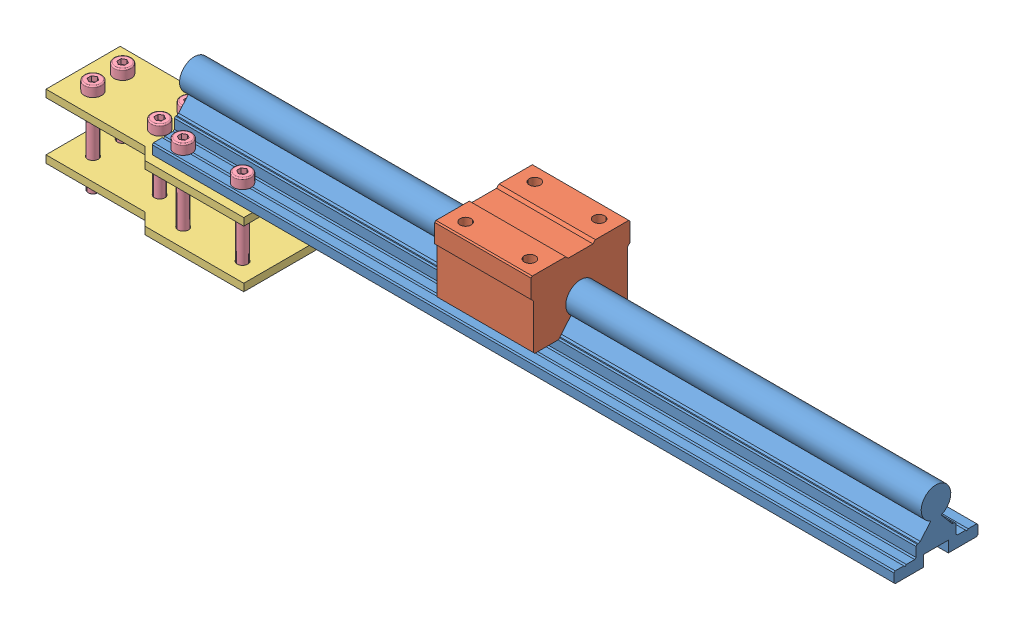
SolidWorks assembly SBR12, configuration 默认. Lengths in mm.
Overall size (345 72.4 40).
20 component instances, 5 part files, 34 mates.
Components (placement in the parent):
- SBR12SA-1: SBR12SA [默认] at (-161.757 5.2695 300) size (300 26.4 34)
- SBR12UU-1: SBR12UU [默认] at (-5.5215 16.7426 300) x (0 0 1) z (-1 0 0) size (40 27.6 39)
- 滑轨固定玻纤下-1: 滑轨固定玻纤下 [Default] at (-161.757 -6.8574 300) x (-1 0 0) z (0 -1 0) size (85 40 3)
- 滑轨固定玻纤下-2: 滑轨固定玻纤下 [Default] at (-161.757 -29.8574 300) x (-1 0 0) z (0 -1 0) size (85 40 3)
- hexagon socket head cap screws gb-3: hexagon socket head cap screws gb [GB_FASTENER_SCREWS_HSHCS M4X35-N] at (-129.757 1.6426 287.5) x (0 -1 0) z (0 0 1) size (39 7 7)
- hexagon socket head cap screws gb-4: hexagon socket head cap screws gb [GB_FASTENER_SCREWS_HSHCS M4X35-N] at (-153.757 1.6426 287.5) x (0 -1 0) z (0 0 1) size (39 7 7)
- hexagon socket head cap screws gb-5: hexagon socket head cap screws gb [GB_FASTENER_SCREWS_HSHCS M4X35-N] at (-129.757 1.6426 312.5) x (0 -1 0) z (0 0 1) size (39 7 7)
- hexagon socket head cap screws gb-6: hexagon socket head cap screws gb [GB_FASTENER_SCREWS_HSHCS M4X35-N] at (-153.757 1.6426 312.5) x (0 -1 0) z (0 0 1) size (39 7 7)
- hexagon socket head cap screws gb-7: hexagon socket head cap screws gb [GB_FASTENER_SCREWS_HSHCS M4X35-N] at (-169.757 -2.8574 294) x (0 -1 0) z (0 0 1) size (39 7 7)
- hexagon socket head cap screws gb-9: hexagon socket head cap screws gb [GB_FASTENER_SCREWS_HSHCS M4X35-N] at (-169.757 -2.8574 306) x (0 -1 0) z (0 0 1) size (39 7 7)
- hexagon socket head cap screws gb-10: hexagon socket head cap screws gb [GB_FASTENER_SCREWS_HSHCS M4X35-N] at (-196.757 -2.8574 294) x (0 -1 0) z (0 0 1) size (39 7 7)
- hexagon socket head cap screws gb-11: hexagon socket head cap screws gb [GB_FASTENER_SCREWS_HSHCS M4X35-N] at (-196.757 -2.8574 306) x (0 -1 0) z (0 0 1) size (39 7 7)
- hex nuts, style 1-grades ab gb-3: hex nuts, style 1-grades ab gb [GB_FASTENER_NUT_SNAB1 M4-N] at (-196.757 -33.0314 294) x (0.999704 0 0.024348) z (0 1 0) size (8.08 7 3.2)
- hex nuts, style 1-grades ab gb-4: hex nuts, style 1-grades ab gb [GB_FASTENER_NUT_SNAB1 M4-N] at (-196.757 -32.8857 306) x (1 0 0) z (0 1 0) size (8.08 7 3.2)
- hex nuts, style 1-grades ab gb-5: hex nuts, style 1-grades ab gb [GB_FASTENER_NUT_SNAB1 M4-N] at (-153.757 -32.9934 312.5) x (1 0 0) z (0 1 0) size (8.08 7 3.2)
- hex nuts, style 1-grades ab gb-6: hex nuts, style 1-grades ab gb [GB_FASTENER_NUT_SNAB1 M4-N] at (-153.757 -32.9092 287.5) x (1 0 0) z (0 1 0) size (8.08 7 3.2)
- hex nuts, style 1-grades ab gb-7: hex nuts, style 1-grades ab gb [GB_FASTENER_NUT_SNAB1 M4-N] at (-129.757 -32.9003 287.5) x (1 0 0) z (0 1 0) size (8.08 7 3.2)
- hex nuts, style 1-grades ab gb-8: hex nuts, style 1-grades ab gb [GB_FASTENER_NUT_SNAB1 M4-N] at (-129.757 -33.0006 312.5) x (1 0 0) z (0 1 0) size (8.08 7 3.2)
- hex nuts, style 1-grades ab gb-9: hex nuts, style 1-grades ab gb [GB_FASTENER_NUT_SNAB1 M4-N] at (-169.757 -33.0168 294) x (1 0 0) z (0 1 0) size (8.08 7 3.2)
- hex nuts, style 1-grades ab gb-10: hex nuts, style 1-grades ab gb [GB_FASTENER_NUT_SNAB1 M4-N] at (-169.757 -32.8923 306) x (1 0 0) z (0 1 0) size (8.08 7 3.2)
Mates (geometry in assembly coordinates):
- Concentric1: concentric: cylinder of assembly; cylinder of assembly; cylinder of SBR12SA-1 through (138.243 13.5426 300) axis (-1 0 0) radius 6; cylinder of SBR12UU-1 through (-44.5215 13.5426 300) axis (1 0 0) radius 6
- Parallel1: parallel: plane of assembly; plane of assembly; plane of SBR12SA-1 through (138.243 -2.3574 313) normal (0 1 0); plane of SBR12UU-1 through (-44.5215 2.9426 308.8945) normal (0 -1 0)
- Distance1: limit distance = 117.2355 mm: plane of assembly; plane of assembly; plane of SBR12UU-1 through (-44.5215 13.5426 300) normal (-1 0 0); plane of SBR12SA-1 through (-161.757 13.5426 300) normal (-1 0 0)
- Inplace1: in place: plane of SBR12SA-1 through (138.243 -6.8574 283.5) normal (0 -1 0); plane of ? through (0 -6.8574 0) normal (0 -1 0); moOrthogonalPlaneRef_w of SBR12SA-1 through (138.243 -6.8574 283.5) normal (0 -1 0); plane of ? through (0 -6.8574 0) normal (0 0 -1); plane of SBR12SA-1 through (138.243 -6.8574 283.5) normal (0 -1 0); plane of ? through (0 -6.8574 0) normal (-1 0 0); plane of SBR12SA-1 through (138.243 -6.8574 283.5) normal (0 -1 0); unknown of 滑轨固定玻纤下-1
- Coincident1: coincident: plane of assembly; plane of assembly; plane of SBR12SA-1; plane of 滑轨固定玻纤下-1
- Coincident2: coincident: plane of assembly; plane of assembly; moOrthogonalPlaneRef_w of SBR12SA-1 through (-161.757 -6.8574 300) normal (0 0 -1); plane of 滑轨固定玻纤下-1 through (-161.757 -6.8574 300) normal (0 0 -1)
- Coincident3: coincident: plane of assembly; plane of assembly; moOrthogonalPlaneRef_w of SBR12SA-1 through (-161.757 -6.8574 300) normal (1 0 0); plane of 滑轨固定玻纤下-1 through (-161.757 -6.8574 300) normal (-1 0 0)
- Coincident4: coincident: plane of assembly; plane of assembly; plane of 滑轨固定玻纤下-1 through (-206.757 -9.8574 285) normal (-1 0 0); plane of 滑轨固定玻纤下-2 through (-206.757 -32.8574 285) normal (-1 0 0)
- Coincident5: coincident: plane of assembly; plane of assembly; plane of 滑轨固定玻纤下-1 through (-166.757 -9.8574 285) normal (0 0 -1); plane of 滑轨固定玻纤下-2 through (-166.757 -32.8574 285) normal (0 0 -1)
- Distance2: distance = 20 mm: plane of assembly; plane of assembly; plane of 滑轨固定玻纤下-2 through (-161.757 -29.8574 300) normal (0 1 0); plane of 滑轨固定玻纤下-1 through (-161.757 -9.8574 300) normal (0 -1 0)
- Concentric7: concentric: cylinder of assembly; cylinder of assembly; cylinder of SBR12SA-1 through (-129.757 3.1426 287.5) axis (0 -1 0) radius 2.15; cylinder of hexagon socket head cap screws gb-3 through (-129.757 -37.3574 287.5) axis (0 1 0) radius 2
- Coincident11: coincident: plane of assembly; plane of assembly; plane of SBR12SA-1 through (138.243 -2.3574 288) normal (0 1 0); plane of hexagon socket head cap screws gb-3 through (-129.757 -2.3574 287.5) normal (0 -1 0)
- Concentric8: concentric: cylinder of assembly; cylinder of assembly; cylinder of SBR12SA-1 through (-153.757 3.1426 287.5) axis (0 -1 0) radius 2.15; cylinder of hexagon socket head cap screws gb-4 through (-153.757 -37.3574 287.5) axis (0 1 0) radius 2
- Coincident12: coincident: plane of assembly; plane of assembly; plane of SBR12SA-1 through (138.243 -2.3574 288) normal (0 1 0); plane of hexagon socket head cap screws gb-4 through (-153.757 -2.3574 287.5) normal (0 -1 0)
- Concentric9: concentric: cylinder of assembly; cylinder of assembly; cylinder of SBR12SA-1 through (-129.757 3.1426 312.5) axis (0 -1 0) radius 2.15; cylinder of hexagon socket head cap screws gb-5 through (-129.757 -37.3574 312.5) axis (0 1 0) radius 2
- Coincident13: coincident: plane of assembly; plane of assembly; plane of SBR12SA-1 through (138.243 -2.3574 308.6004) normal (0 1 0); plane of hexagon socket head cap screws gb-5 through (-129.757 -2.3574 312.5) normal (0 -1 0)
- Concentric10: concentric: cylinder of assembly; cylinder of assembly; cylinder of SBR12SA-1 through (-153.757 3.1426 312.5) axis (0 -1 0) radius 2.15; cylinder of hexagon socket head cap screws gb-6 through (-153.757 -37.3574 312.5) axis (0 1 0) radius 2
- Coincident14: coincident: plane of assembly; plane of assembly; plane of SBR12SA-1 through (138.243 -2.3574 308.6004) normal (0 1 0); plane of hexagon socket head cap screws gb-6 through (-153.757 -2.3574 312.5) normal (0 -1 0)
- Concentric11: concentric: cylinder of assembly; cylinder of assembly; cylinder of 滑轨固定玻纤下-1 through (-169.757 -9.8574 294) axis (0 1 0) radius 2.15; cylinder of hexagon socket head cap screws gb-7 through (-169.757 -41.8574 294) axis (0 1 0) radius 2
- Coincident15: coincident: plane of assembly; plane of assembly; plane of 滑轨固定玻纤下-1 through (-161.757 -6.8574 300) normal (0 1 0); plane of hexagon socket head cap screws gb-7 through (-169.757 -6.8574 294) normal (0 -1 0)
- Concentric13: concentric: cylinder of assembly; cylinder of assembly; cylinder of 滑轨固定玻纤下-1 through (-169.757 -9.8574 306) axis (0 1 0) radius 2.15; cylinder of hexagon socket head cap screws gb-9 through (-169.757 -41.8574 306) axis (0 1 0) radius 2
- Coincident16: coincident: plane of assembly; plane of assembly; plane of 滑轨固定玻纤下-1 through (-161.757 -6.8574 300) normal (0 1 0); plane of hexagon socket head cap screws gb-9 through (-169.757 -6.8574 306) normal (0 -1 0)
- Concentric14: concentric: cylinder of assembly; cylinder of assembly; cylinder of 滑轨固定玻纤下-1 through (-196.757 -9.8574 294) axis (0 1 0) radius 2.15; cylinder of hexagon socket head cap screws gb-10 through (-196.757 -41.8574 294) axis (0 1 0) radius 2
- Coincident17: coincident: plane of assembly; plane of assembly; plane of 滑轨固定玻纤下-1 through (-161.757 -6.8574 300) normal (0 1 0); plane of hexagon socket head cap screws gb-10 through (-196.757 -6.8574 294) normal (0 -1 0)
- Concentric15: concentric: cylinder of assembly; cylinder of assembly; cylinder of 滑轨固定玻纤下-1 through (-196.757 -9.8574 306) axis (0 1 0) radius 2.15; cylinder of hexagon socket head cap screws gb-11 through (-196.757 -41.8574 306) axis (0 1 0) radius 2
- Coincident18: coincident: plane of assembly; plane of assembly; plane of 滑轨固定玻纤下-1 through (-161.757 -6.8574 300) normal (0 1 0); plane of hexagon socket head cap screws gb-11 through (-196.757 -6.8574 306) normal (0 -1 0)
- Concentric26: concentric: cylinder of assembly; cylinder of assembly; cylinder of hexagon socket head cap screws gb-10 through (-196.757 -41.8574 294) axis (0 1 0) radius 2; cylinder of hex nuts, style 1-grades ab gb-3 through (-196.757 -36.2314 294) axis (0 1 0) radius 1.621
- Concentric27: concentric: cylinder of assembly; cylinder of assembly; cylinder of hexagon socket head cap screws gb-11 through (-196.757 -41.8574 306) axis (0 1 0) radius 2; cylinder of hex nuts, style 1-grades ab gb-4 through (-196.757 -36.0857 306) axis (0 1 0) radius 1.621
- Concentric28: concentric: cylinder of assembly; cylinder of assembly; cylinder of hexagon socket head cap screws gb-6 through (-153.757 -37.3574 312.5) axis (0 1 0) radius 2; cylinder of hex nuts, style 1-grades ab gb-5 through (-153.757 -36.1934 312.5) axis (0 1 0) radius 1.621
- Concentric29: concentric: cylinder of assembly; cylinder of assembly; cylinder of hexagon socket head cap screws gb-4 through (-153.757 -37.3574 287.5) axis (0 1 0) radius 2; cylinder of hex nuts, style 1-grades ab gb-6 through (-153.757 -36.1092 287.5) axis (0 1 0) radius 1.621
- Concentric30: concentric: cylinder of assembly; cylinder of assembly; cylinder of hexagon socket head cap screws gb-3 through (-129.757 -37.3574 287.5) axis (0 1 0) radius 2; cylinder of hex nuts, style 1-grades ab gb-7 through (-129.757 -36.1003 287.5) axis (0 1 0) radius 1.621
- Concentric31: concentric: cylinder of assembly; cylinder of assembly; cylinder of hexagon socket head cap screws gb-5 through (-129.757 -37.3574 312.5) axis (0 1 0) radius 2; cylinder of hex nuts, style 1-grades ab gb-8 through (-129.757 -36.2006 312.5) axis (0 1 0) radius 1.621
- Concentric32: concentric: cylinder of assembly; cylinder of assembly; cylinder of hexagon socket head cap screws gb-7 through (-169.757 -41.8574 294) axis (0 1 0) radius 2; cylinder of hex nuts, style 1-grades ab gb-9 through (-169.757 -36.2168 294) axis (0 1 0) radius 1.621
- Concentric33: concentric: cylinder of assembly; cylinder of assembly; cylinder of hexagon socket head cap screws gb-9 through (-169.757 -41.8574 306) axis (0 1 0) radius 2; cylinder of hex nuts, style 1-grades ab gb-10 through (-169.757 -36.0923 306) axis (0 1 0) radius 1.621
